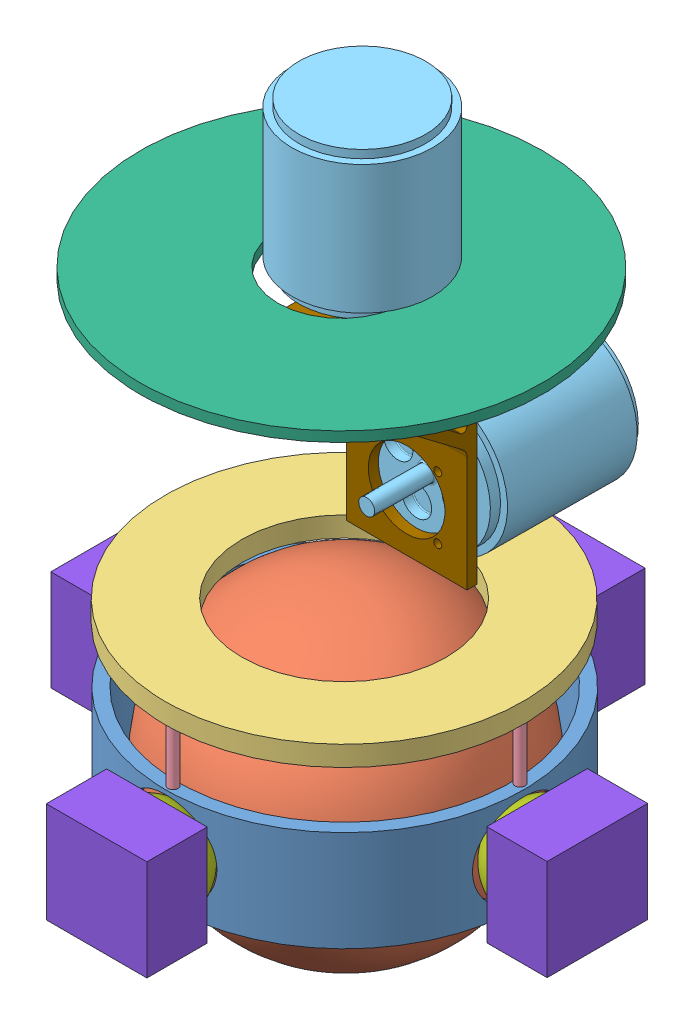
SolidWorks assembly BASEFRAME, configuration Default. Lengths in mm.
Overall size (247.77 358.61 250.32).
24 component instances, 10 part files, 0 mates.
Components (placement in the parent):
- Part3^BASEFRAME-1: Part3^BASEFRAME [Default] at origin (virtual)
- Ring-2: Ring [Default] at (56.5454 70.1965 140.0221) size (177.8 50 177.8)
- Ball-2: Ball [Default] at (56.3718 89.7946 139.2771) size (152.72 152.4 152.72)
- topring-1: topring [Default] at (56.4499 148.2812 140.2183) size (177.8 10 177.8)
- ringsupport-2: ringsupport [Default] at (141.6171 118.3743 137.934) size (5 30 5)
- ringsupport-3: ringsupport [Default] at (56.4881 119.5438 225.2557) size (5 30 5)
- ringsupport-4: ringsupport [Default] at (52.9689 119.0363 54.4711) size (5 30 5)
- ringsupport-5: ringsupport [Default] at (-29.2226 118.4996 135.95) size (5 30 5)
- motormodel-1: motormodel [Default] at (59.436 372.2093 134.17) x (0 -1 0) z (-0.765805 0 0.643073) size (103 70 70)
- motormodel-2: motormodel [Default] at (59.1428 193.9149 27.9507) x (-0.007304 0.000852 0.999973) z (-0.340585 -0.940212 -0.001686) size (103 70 70)
- uppercasing-2: uppercasing [Default] at (56.5112 301.7694 141.6583) x (-1 0 0) z (0 0 1) size (200 5 200)
- BearingContainerAsm-1: BearingContainerAsm [Default] at (204.8774 159.502 110.4056) x (0 -1 0) z (-1 0 0) size (50 50 49.48)
  - miniball-2: miniball [Default] at (64.8074 28.9122 72.7375) size (49 49 49)
  - container-3: container [Default] at (97.5898 25.7275 23.2563) x (-1 0 0) z (0 0 -1) size (50 50 30)
- BearingContainerAsm-2: BearingContainerAsm [Default] at (122.3275 65.8552 287.5952) x (-1 0 0) z (0 0 -1) size (50 50 49.48)
  - miniball-2: miniball [Default] at (64.8074 28.9122 72.7375) size (49 49 49)
  - container-3: container [Default] at (97.5898 25.7275 23.2563) x (-1 0 0) z (0 0 -1) size (50 50 30)
- BearingContainerAsm-3: BearingContainerAsm [Default] at (-9.934 65.7824 -9.2346) size (50 50 49.48)
  - miniball-2: miniball [Default] at (64.8074 28.9122 72.7375) size (49 49 49)
  - container-3: container [Default] at (97.5898 25.7275 23.2563) x (-1 0 0) z (0 0 -1) size (50 50 30)
- BearingContainerAsm-4: BearingContainerAsm [Default] at (-89.4008 65.902 203.1973) x (0 0 -1) z (1 0 0) size (50 50 49.48)
  - miniball-2: miniball [Default] at (64.8074 28.9122 72.7375) size (49 49 49)
  - container-3: container [Default] at (97.5898 25.7275 23.2563) x (-1 0 0) z (0 0 -1) size (50 50 30)
- lbrac_v2-1: lbrac_v2 [Default] at (87.615 216.9767 144.8563) size (60 106.6 60)
